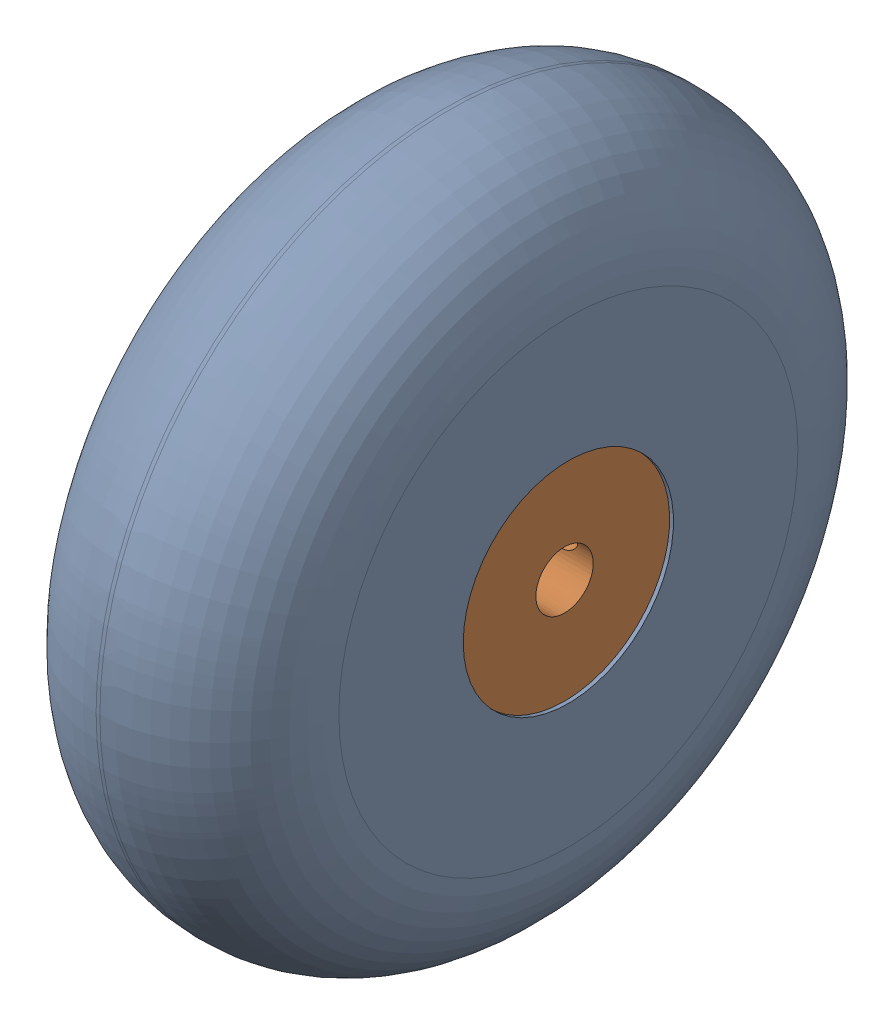
SolidWorks assembly rasm_wheelAssem, configuration Default. Lengths in mm.
Overall size (25.4 73.02 73.03).
2 component instances, 2 part files, 0 mates.
Components (placement in the parent):
- rasm_70 mm scooter wheel-1: rasm_70 mm scooter wheel [Default] at (20.8259 39.2832 48.0628) x (0 -1 0) z (0 0 1) size (73.03 25.4 73.03)
- rasm_Aluminum scooter wheel adapter for 6 mm shaft-1: rasm_Aluminum scooter wheel adapter for 6 mm shaft [Default] at (45.8259 39.2832 48.0628) x (0 -0.801395 -0.598135) z (0 0.598135 -0.801395) size (22 18.5 22)
